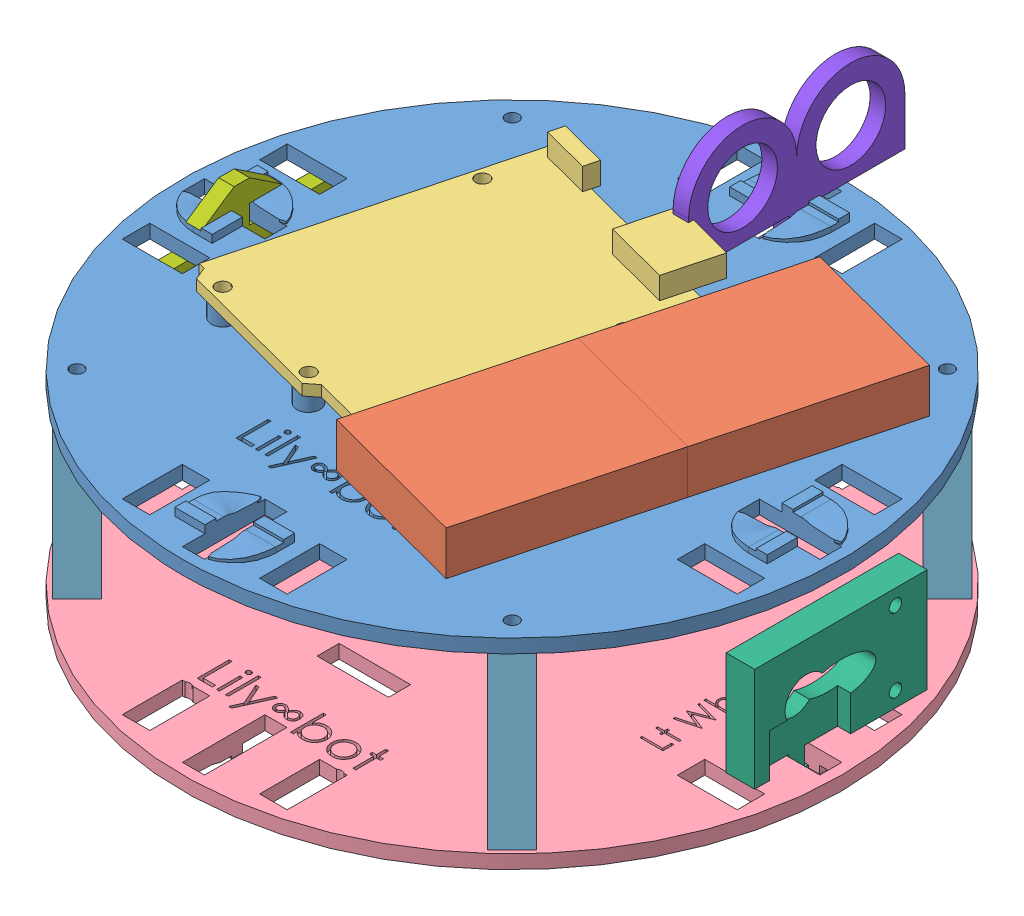
SolidWorks assembly LilyBot, configuration Default. Lengths in mm.
Overall size (152.4 77.33 164.43).
13 component instances, 8 part files, 32 mates.
Components (placement in the parent):
- New Lily top-1: New Lily top [Default] at (52.5884 109.2865 96.6599) size (152.4 6.99 152.4)
- Small breadboard-1: Small breadboard [Default] at (75.5494 112.4615 119.6495) x (0.255002 0 -0.96694) z (0.96694 0 0.255002) size (45.72 10.16 35.56)
- Small breadboard-2: Small breadboard [Default] at (87.2081 112.4615 75.441) x (0.255002 0 -0.96694) z (0.96694 0 0.255002) size (45.72 10.16 35.56)
- Uno chip-1: Uno chip [Default] at (35.5331 116.2715 94.1581) x (-0.255002 0 0.96694) z (0 1 0) size (74.93 53.34 7.62)
- New Lily Bottom-1: New Lily Bottom [Default] at (52.5884 69.2865 96.6599) x (0 0 -1) z (-1 0 0) size (152.4 4.98 152.4)
- Lily standoffs-1: Lily standoffs [Default] at (2.299 69.2865 146.9493) x (0.707107 0 -0.707107) z (0.707107 0 0.707107) size (8 40 8)
- Lily standoffs-2: Lily standoffs [Default] at (2.299 69.2865 46.3704) x (0.707107 0 -0.707107) z (0.707107 0 0.707107) size (8 40 8)
- Lily standoffs-3: Lily standoffs [Default] at (102.8778 69.2865 46.3704) x (0.707107 0 -0.707107) z (0.707107 0 0.707107) size (8 40 8)
- Lily standoffs-4: Lily standoffs [Default] at (102.8778 69.2865 146.9493) x (0.707107 0 -0.707107) z (0.707107 0 0.707107) size (8 40 8)
- Motor Attachment -1: Motor Attachment  [Default] at (-9.7559 67.099 96.7869) x (0 0 -1) z (0 1 0) size (39.88 6.62 33.45)
- Motor Attachment -2: Motor Attachment  [Default] at (118.5141 67.099 96.7869) x (0 0 -1) z (0 1 0) size (39.88 6.62 33.45)
- IR sensor Attachment -5: IR sensor Attachment  [Default] at (-13.3373 111.474 96.7869) x (0 0 -1) z (0 -1 0) size (45 3.58 24.45)
- Sonar sensor Attachment -1: Sonar sensor Attachment  [Default] at (51.547 111.474 33.4398) x (0 0 1) z (0 1 0) size (50.01 3.58 32.96)
Mates (geometry in assembly coordinates):
- Coincident2: coincident anti-aligned: plane of New Lily top-1 through (52.5884 112.4615 96.6599) normal (0 1 0); plane of Small breadboard-1 through (75.5494 112.4615 119.6495) normal (0 -1 0)
- Coincident3: coincident anti-aligned: plane of New Lily top-1 through (52.5884 112.4615 96.6599) normal (0 1 0); plane of Small breadboard-2 through (87.2081 112.4615 75.441) normal (0 -1 0)
- Coincident5: coincident anti-aligned: plane of New Lily top-1 through (17.4326 116.2715 68.1862) normal (0 1 0); plane of Uno chip-1 through (35.5331 116.2715 94.1581) normal (0 -1 0)
- Coincident6: coincident aligned: plane of Small breadboard-1 through (86.9122 122.6215 146.2877) normal (0.96694 0 0.255002); plane of Small breadboard-2 through (98.5709 122.6215 102.0792) normal (0.96694 0 0.255002)
- Coincident7: coincident anti-aligned: plane of Small breadboard-1 through (98.5709 122.6215 102.0792) normal (0.255002 0 -0.96694); plane of Small breadboard-2 through (98.5709 122.6215 102.0792) normal (-0.255002 0 0.96694)
- Concentric1: concentric anti-aligned: circle of New Lily top-1; circle of New Lily Bottom-1
- Coincident11: coincident anti-aligned: plane of New Lily top-1 through (52.5884 109.2865 96.6599) normal (0 -1 0); plane of Lily standoffs-4 through (102.8778 109.2865 146.9493) normal (0 1 0)
- Coincident12: coincident anti-aligned: plane of New Lily top-1 through (52.5884 109.2865 96.6599) normal (0 -1 0); plane of Lily standoffs-1 through (2.299 109.2865 146.9493) normal (0 1 0)
- Coincident13: coincident anti-aligned: plane of New Lily top-1 through (52.5884 109.2865 96.6599) normal (0 -1 0); plane of Lily standoffs-2 through (2.299 109.2865 46.3704) normal (0 1 0)
- Coincident14: coincident anti-aligned: plane of New Lily top-1 through (52.5884 109.2865 96.6599) normal (0 -1 0); plane of Lily standoffs-3 through (102.8778 109.2865 46.3704) normal (0 1 0)
- Coincident15: coincident anti-aligned: plane of New Lily Bottom-1 through (52.5884 69.2865 96.6599) normal (0 1 0); plane of Lily standoffs-3 through (102.8778 69.2865 46.3704) normal (0 -1 0)
- Parallel3: parallel anti-aligned: plane of Lily standoffs-2 through (2.299 109.2865 52.0273) normal (0.707107 0 0.707107); plane of Lily standoffs-4 through (97.221 109.2865 146.9493) normal (-0.707107 0 -0.707107)
- Coincident17: coincident aligned: plane of Lily standoffs-2 through (2.299 109.2865 52.0273) normal (-0.707107 0 0.707107); plane of Lily standoffs-4 through (102.8778 109.2865 152.6061) normal (-0.707107 0 0.707107)
- Coincident18: coincident aligned: plane of Lily standoffs-1 through (2.299 109.2865 152.6061) normal (0.707107 0 0.707107); plane of Lily standoffs-3 through (102.8778 109.2865 52.0273) normal (0.707107 0 0.707107)
- Parallel4: parallel anti-aligned: plane of Lily standoffs-1 through (7.9558 109.2865 146.9493) normal (0.707107 0 -0.707107); plane of Lily standoffs-3 through (102.8778 109.2865 52.0273) normal (-0.707107 0 0.707107)
- Parallel5: parallel aligned: plane of Small breadboard-1 through (86.9122 122.6215 146.2877) normal (0.96694 0 0.255002); plane of Uno chip-1 through (70.0655 118.8115 67.8026) normal (0.96694 0 0.255002)
- Coincident20: coincident anti-aligned: plane of New Lily Bottom-1 through (-9.7559 64.9115 87.1349) normal (0 -1 0); plane of Motor Attachment -1 through (-13.3373 64.9115 96.7869) normal (0 1 0)
- Coincident21: coincident anti-aligned: plane of New Lily Bottom-1 through (-9.7559 69.2865 96.6599) normal (-1 0 0); plane of Motor Attachment -1 through (-9.7559 67.099 96.7869) normal (1 0 0)
- Coincident22: coincident aligned: line of New Lily Bottom-1 through (-13.3373 64.9115 106.1849) axis (1 0 0); line of Motor Attachment -1 through (-13.3373 64.9115 106.1849) axis (1 0 0)
- Coincident28: coincident anti-aligned: plane of New Lily top-1 through (-9.7559 113.6615 106.1849) normal (0 1 0); plane of IR sensor Attachment -5 through (-9.7559 113.6615 96.7869) normal (0 -1 0)
- Coincident29: coincident anti-aligned: plane of New Lily top-1 through (-9.7559 109.2865 96.6599) normal (-1 0 0); plane of IR sensor Attachment -5 through (-9.7559 111.474 96.7869) normal (1 0 0)
- Coincident30: coincident aligned: line of New Lily top-1 through (-9.7559 113.6615 106.1849) axis (-1 0 0); line of IR sensor Attachment -5 through (-9.7559 113.6615 106.1849) axis (-1 0 0)
- Concentric2: concentric aligned: cylinder of New Lily top-1 through (2.299 109.2865 146.9493) axis (0 1 0) radius 1.5; cylinder of Lily standoffs-1 through (2.299 69.2865 146.9493) axis (0 1 0) radius 1.45
- Concentric3: concentric anti-aligned: cylinder of New Lily Bottom-1 through (2.299 69.2865 146.9493) axis (0 -1 0) radius 1.5; cylinder of Lily standoffs-1 through (2.299 69.2865 146.9493) axis (0 1 0) radius 1.45
- Concentric4: concentric aligned: cylinder of New Lily top-1 through (2.299 109.2865 46.3704) axis (0 1 0) radius 1.5; cylinder of Lily standoffs-2 through (2.299 69.2865 46.3704) axis (0 1 0) radius 1.45
- Concentric5: concentric aligned: cylinder of New Lily top-1 through (102.8778 109.2865 46.3704) axis (0 1 0) radius 1.5; cylinder of Lily standoffs-3 through (102.8778 69.2865 46.3704) axis (0 1 0) radius 1.45
- Concentric6: concentric aligned: cylinder of New Lily top-1 through (102.8778 109.2865 146.9493) axis (0 1 0) radius 1.5; cylinder of Lily standoffs-4 through (102.8778 69.2865 146.9493) axis (0 1 0) radius 1.45
- Coincident31: coincident anti-aligned: plane of New Lily top-1 through (62.1134 113.6615 30.7342) normal (0 1 0); plane of Sonar sensor Attachment -1 through (55.1284 113.6615 33.4398) normal (0 -1 0)
- Coincident32: coincident anti-aligned: plane of New Lily top-1 through (55.1284 114.2615 22.9999) normal (-1 0 0); plane of Sonar sensor Attachment -1 through (55.1284 111.474 33.4398) normal (1 0 0)
- Coincident33: coincident anti-aligned: plane of New Lily Bottom-1 through (52.5884 69.2865 96.6599) normal (0 1 0); plane of Motor Attachment -2 through (114.9327 69.2865 96.7869) normal (0 -1 0)
- Coincident35: coincident anti-aligned: plane of New Lily Bottom-1 through (118.5141 69.2865 96.6599) normal (-1 0 0); plane of Motor Attachment -2 through (118.5141 67.099 96.7869) normal (1 0 0)
- Coincident36: coincident aligned: line of New Lily Bottom-1 through (114.9327 64.9115 106.1849) axis (1 0 0); line of Motor Attachment -2 through (114.9327 64.9115 106.1849) axis (1 0 0)
